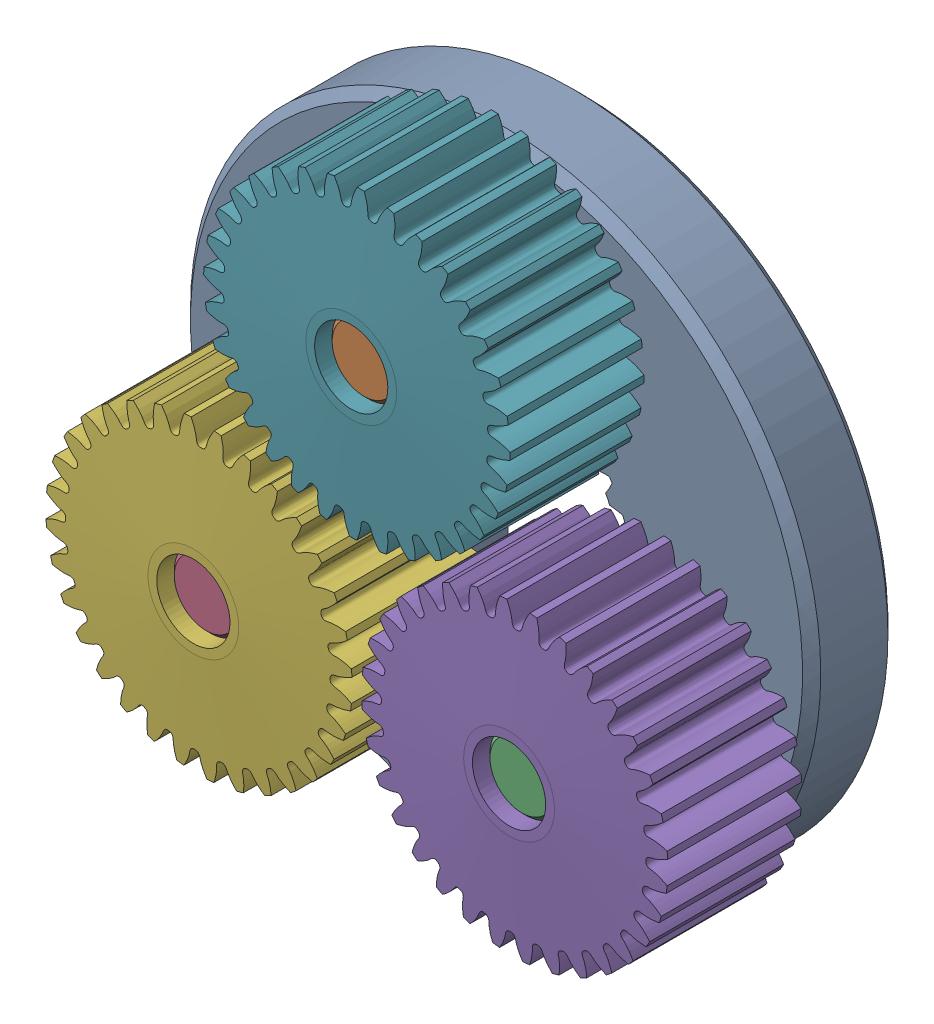
SolidWorks assembly 217-2820 Rev1_Public, configuration Default. Lengths in mm.
Overall size (39.26 38.9 12.7).
8 component instances, 3 part files, 0 mates.
Components (placement in the parent):
- 217-2625-100-1: 217-2625-100 [Default] at origin size (39.26 38.9 12.7)
  - 217-2625-008 Rev1-1: 217-2625-008 Rev1 [Default] at origin size (34.7 34.7 4.7)
  - 217-2625-010 Rev1-1: 217-2625-010 Rev1 [Default] at (0 10.193 3.65) x (0.999813 0.019336 0) z (0 0 1) size (4 4 12)
  - 217-2625-010 Rev1-2: 217-2625-010 Rev1 [Default] at (8.691 -5.3258 3.65) size (4 4 12)
  - 217-2625-010 Rev1-3: 217-2625-010 Rev1 [Default] at (-8.691 -5.3258 3.65) size (4 4 12)
  - 217-2625-005 Rev1_Planet_Revolving_Follower01-1: 217-2625-005 Rev1_Planet_Revolving_Follower01 [Default] at (8.691 -5.3258 6.35) x (0.932816 0.360354 0) z (0 0 1) size (16.91 16.92 8)
  - 217-2625-005 Rev1_Planet_Revolving_Follower01-2: 217-2625-005 Rev1_Planet_Revolving_Follower01 [Default] at (-8.691 -5.3258 6.35) x (-0.932788 -0.360426 0) z (0 0 1) size (16.91 16.92 8)
  - 217-2625-005 Rev1_Planet_Revolving_Follower01-3: 217-2625-005 Rev1_Planet_Revolving_Follower01 [Default] at (0 10.193 6.35) x (0.893583 0.448898 0) z (0 0 1) size (16.91 16.92 8)
